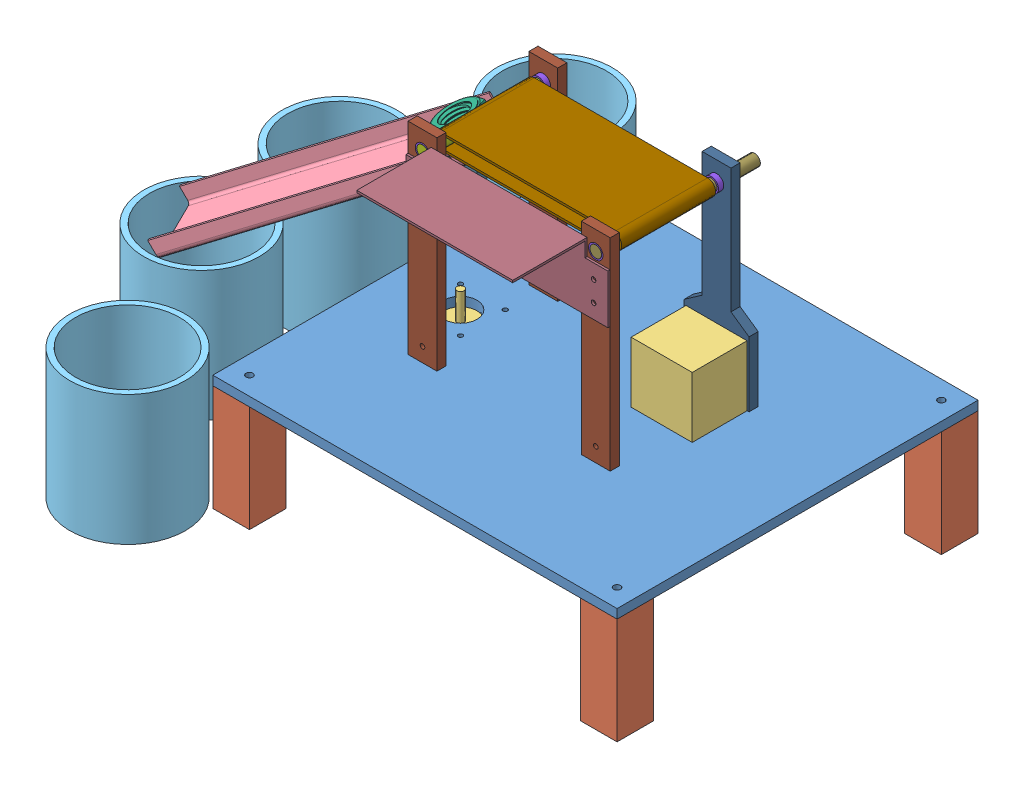
SolidWorks assembly PlatformAssembly, configuration Default. Lengths in mm.
Overall size (404.97 220 375.68).
24 component instances, 14 part files, 23 mates.
Components (placement in the parent):
- Platform-1: Platform [Default] at origin size (280 6.35 250)
- Legs-1: Legs [Default] at (-127.3 -73.65 112.3) size (25.4 73.65 25.4)
- Legs-2: Legs [Default] at (-127.3 -73.65 -112.3) size (25.4 73.65 25.4)
- Legs-3: Legs [Default] at (127.3 -73.65 112.3) x (-1 0 0) z (0 0 -1) size (25.4 73.65 25.4)
- Legs-4: Legs [Default] at (127.3 -73.65 -112.3) x (-1 0 0) z (0 0 -1) size (25.4 73.65 25.4)
- StepperMotor-1: StepperMotor [Default] at (-93.45 -38 0) size (42.3 57 42)
- P_chute-1: P_chute [Default] at (-82.7407 113.0654 -5.2808) x (-0.896889 0 0.442256) z (-0.442256 0 -0.896889) size (166 102.77 50)
- P_Cups-1: P_Cups [Default] at (0 -73.65 0) x (0 0 1) z (-1 0 0) size (375.68 90 128.78)
- 94812A630_NYLON 6-6 HEX NUT-1: 94812A630_NYLON 6-6 HEX NUT [94812A630] at (-92.4006 116.2417 -0.5175) x (0.776728 0.5 -0.383005) z (0.442256 0 0.896889) size (28.18 18.27 32.54)
- A_CONVEYOR-1: A_CONVEYOR [Default] at (68.3187 -63.5604 -123.0839) x (-1 0 0) z (0 1 0) size (152.5 161.5 140)
  - P_CONVEYOR_SHAFT-2: P_CONVEYOR_SHAFT [Default] at (143.0687 168.0839 196.6604) x (1 0 0) z (0 -1 0) size (8 8 90)
  - P_CONVEYOR_BUSHING-1: P_CONVEYOR_BUSHING [Default] at (23.0687 88.0839 196.6604) x (1 0 0) z (0 0 -1) size (10 10 10)
  - P_CONVEYOR_BUSHING-2: P_CONVEYOR_BUSHING [Default] at (23.0687 168.0839 196.6604) x (1 0 0) z (0 0 -1) size (10 10 10)
  - P_CONVEYOR_BUSHING-3: P_CONVEYOR_BUSHING [Default] at (143.0687 88.0839 196.6604) x (1 0 0) z (0 0 -1) size (10 10 10)
  - P_CONVEYOR_BUSHING-4: P_CONVEYOR_BUSHING [Default] at (143.0687 168.0839 196.6604) x (1 0 0) z (0 0 -1) size (10 10 10)
  - P_CONVEYOR_BELT-1: P_CONVEYOR_BELT [Default] at (23.0687 90.5839 196.6604) size (131 65 11)
  - P_CONVEYOR_LEG_STEPPER_MOUNT-1: P_CONVEYOR_LEG_STEPPER_MOUNT [Default] at (23.0687 78.0839 133.2854) x (-1 0 0) z (0 0 -1) size (45 6.35 140)
  - P_CONVEYOR_LEGS-2: P_CONVEYOR_LEGS [Default] at (143.0687 78.0839 133.2854) x (-1 0 0) z (0 0 -1) size (20 6.35 140)
  - P_CONVEYOR_LEGS-3: P_CONVEYOR_LEGS [Default] at (23.0687 161.7339 133.2854) x (-1 0 0) z (0 0 -1) size (20 6.35 140)
  - P_CONVEYOR_LEGS-4: P_CONVEYOR_LEGS [Default] at (143.0687 161.7339 133.2854) x (-1 0 0) z (0 0 -1) size (20 6.35 140)
  - StepperMotor-1: StepperMotor [Default] at (23.0687 122.4339 90.9104) x (-1 0 0) z (0 0 1) size (42.3 57 42)
  - P_CONVEYOR_SHAFT_EXTENDED-2: P_CONVEYOR_SHAFT_EXTENDED [Default] at (23.0687 168.0839 196.6604) x (-0.565285 0 -0.824896) z (0 -1 0) size (8 8 110)
  - P_SENSOR_MOUNT_PLATE-1: P_SENSOR_MOUNT_PLATE [Default] at (113.4906 169.5839 217.0319) x (-1 0 0) z (0 0 1) size (140 51.5 45.5)
- P_steppermotorattachment-1: P_steppermotorattachment [Default] at (-82.0595 86.35 -5.6167) x (0.442256 0 0.896889) z (-0.896889 0 0.442256) size (25 25.4 25.4)
Mates (geometry in assembly coordinates):
- Coincident1: coincident: plane of Platform-1 through (0 0 0) normal (0 0 1); plane of assembly through (0 0 0) normal (0 0 1)
- Coincident2: coincident: plane of Platform-1 through (0 0 0) normal (0 1 0); plane of assembly through (0 0 0) normal (0 1 0)
- Coincident3: coincident: plane of Platform-1 through (0 0 0) normal (1 0 0); plane of assembly through (0 0 0) normal (1 0 0)
- Coincident4: coincident: plane of Platform-1 through (-140 6.35 125) normal (0 0 1); plane of Legs-1 through (-140 0 125) normal (0 0 1)
- Coincident5: coincident: plane of Platform-1 through (-140 6.35 125) normal (-1 0 0); plane of Legs-1 through (-140 0 125) normal (-1 0 0)
- Coincident6: coincident: plane of Platform-1 through (0 0 0) normal (0 -1 0); plane of Legs-1 through (-127.3 0 112.3) normal (0 1 0)
- Coincident10: coincident: plane of StepperMotor-1 through (-93.45 -38 0) normal (0 0 1); plane of assembly through (0 0 0) normal (0 0 1)
- Distance1: distance = 25.4 mm: plane of StepperMotor-1 through (-114.6 0 21) normal (-1 0 0); plane of Platform-1 through (-140 6.35 125) normal (-1 0 0)
- Coincident25: coincident: plane of Legs-2 through (-127.3 -73.65 -112.3) normal (0 -1 0); plane of P_Cups-1 through (-176.1902 -73.65 -147.8412) normal (0 -1 0)
- Coincident26: coincident: plane of StepperMotor-1 through (-93.45 -38 0) normal (0 0 1); plane of P_Cups-1 through (0 -73.65 0) normal (0 0 1)
- Coincident32: coincident: plane of P_Cups-1 through (0 -73.65 0) normal (-1 0 0); plane of assembly through (0 0 0) normal (1 0 0)
- Coincident35: coincident: plane of P_chute-1 through (-93.7971 113.0654 -27.703) normal (-0.448444 0.866025 0.221128); plane of 94812A630_NYLON 6-6 HEX NUT-1 through (-103.2929 102.1512 -4.2159) normal (0.448444 -0.866025 -0.221128)
- Parallel2: parallel: plane of P_chute-1 through (-93.7971 113.0654 -27.703) normal (0.776728 0.5 -0.383005); plane of 94812A630_NYLON 6-6 HEX NUT-1 through (-81.5083 130.3321 3.181) normal (0.776728 0.5 -0.383005)
- Coincident36: coincident: plane of Platform-1 through (0 6.35 0) normal (0 1 0); plane of A_CONVEYOR-1/P_CONVEYOR_LEGS-2 through (-84.75 6.35 -38.65) normal (0 -1 0)
- Coincident38: coincident: plane of P_chute-1 through (-82.7407 113.0654 -5.2808) normal (-0.442256 0 -0.896889); plane of 94812A630_NYLON 6-6 HEX NUT-1 through (-92.4006 116.2417 -0.5175) normal (0.442256 0 0.896889)
- Coincident39: coincident: plane of A_CONVEYOR-1 through (68.3187 -63.5604 0) normal (0 0 1); plane of assembly through (0 0 0) normal (0 0 1)
- Coincident42: coincident: plane of P_chute-1 through (-93.1159 111.75 -28.0389) normal (0.448444 -0.866025 -0.221128); plane of P_steppermotorattachment-1 through (-76.5313 111.75 5.5945) normal (-0.448444 0.866025 0.221128)
- Concentric1: concentric: cylinder of StepperMotor-1 through (-93.45 19 0) axis (0 -1 0) radius 2.5; cylinder of P_steppermotorattachment-1 through (-93.45 86.35 0) axis (0 -1 0) radius 1.8986
- Coincident43: coincident: plane of P_chute-1 through (-93.7971 113.0654 -27.703) normal (0.776728 0.5 -0.383005); line of P_steppermotorattachment-1 through (-76.5313 111.75 5.5945) axis (-0.442256 0 -0.896889)
- Coincident44: coincident: plane of P_chute-1 through (-82.7407 113.0654 -5.2808) normal (-0.442256 0 -0.896889); plane of P_steppermotorattachment-1 through (-82.0595 86.35 -5.6167) normal (0.442256 0 0.896889)
- Coincident46: coincident: plane of Platform-1 through (0 0 0) normal (0 -1 0); plane of StepperMotor-1 through (-93.45 0 0) normal (0 1 0)
- Distance3: distance = 55.25 mm: plane of A_CONVEYOR-1/P_CONVEYOR_LEGS-2 through (-84.75 6.35 -38.65) normal (-1 0 0); plane of Platform-1 through (-140 6.35 125) normal (-1 0 0)
- Distance4: distance = 80 mm: plane of P_steppermotorattachment-1 through (-99.3123 86.35 16.8278) normal (0 -1 0); plane of Platform-1 through (0 6.35 0) normal (0 1 0)
